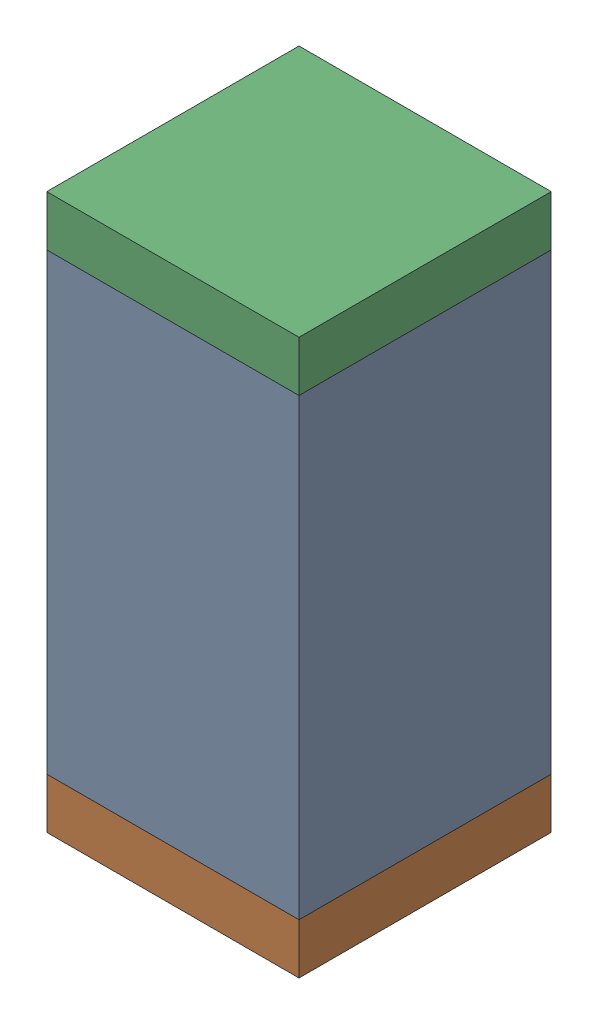
SolidWorks assembly C46, configuration Default. Lengths in mm.
Overall size (0.5 1.1 0.5).
6 component instances, 2 part files, 0 mates.
Components (placement in the parent):
- 791586336-1: 791586336 [Default] at (134.6 39.55 0) size (0.5 0.9 0.5)
  - Extruded_8-1: Extruded_8 [Default] at origin size (0.5 0.9 0.5)
- 810157360-1: 810157360 [Default] at (134.6 39.05 0) size (0.5 0.1 0.5)
  - Extruded_9-1: Extruded_9 [Default] at origin size (0.5 0.1 0.5)
- 810157360-2: 810157360 [Default] at (134.6 40.05 0) size (0.5 0.1 0.5)
  - Extruded_9-1: Extruded_9 [Default] at origin size (0.5 0.1 0.5)
